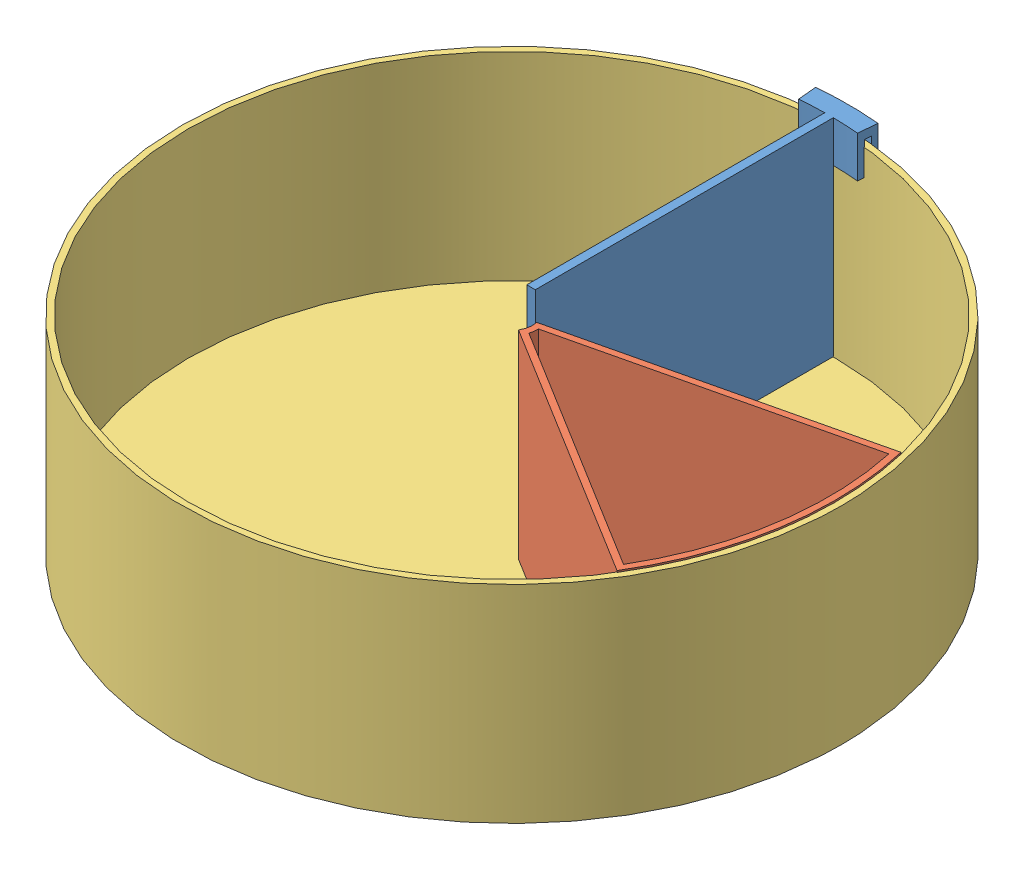
SolidWorks assembly Assem2, configuration Default. Lengths in mm.
Overall size (159.32 53.56 160.89).
3 component instances, 3 part files, 2 mates.
Components (placement in the parent):
- div-2: div [Default] at (-96.6402 13.9584 66.1225) size (15.08 50 76.58)
- cont-1: cont [Default] at (-96.6402 12.7973 66.1225) x (0 0 1) z (0 1 0) size (59.05 73.91 48)
- box-3: box [Default] at (-96.6402 10.3975 66.1225) x (1 0 0) z (0 1 0) size (159.32 159.32 50)
Mates (geometry in assembly coordinates):
- Concentric1: concentric anti-aligned: cylinder of cont-1 through (-96.6402 60.7973 66.1225) axis (0 -1 0) radius 78.16; cylinder of box-3 through (-96.6402 12.3975 66.1225) axis (0 1 0) radius 78.16
- Concentric2: concentric aligned: cylinder of div-2 through (-96.6402 61.9584 66.1225) axis (0 -1 0) radius 79.7319; cylinder of box-3 through (-96.6402 60.3975 66.1225) axis (0 -1 0) radius 79.66
